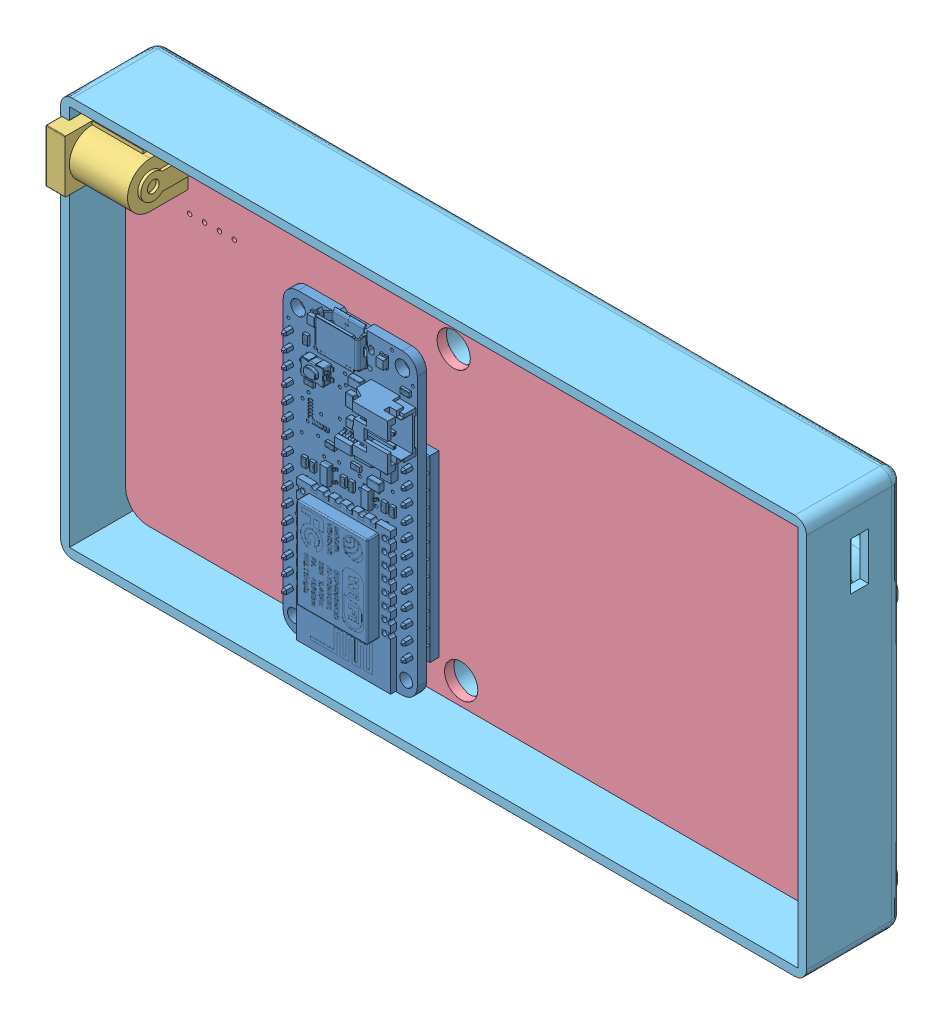
SolidWorks assembly boitierLED, configuration Défaut. Lengths in mm.
Overall size (127 68 83.44).
11 component instances, 5 part files, 1 mates.
Components (placement in the parent):
- me-freeledmodel-1: me-freeledmodel [Défaut] at (-82.6083 85.1585 124.3251) size (125.18 62.87 58.05)
  - Adafruit_ESP8266_Feather_withPinheads-1: Adafruit_ESP8266_Feather_withPinheads [Défaut] at (77.45 -64.5 3.65) x (-1 0 0) z (0 1 0) size (22.89 14.76 51.51)
    - COMPOUND-1: COMPOUND [Défaut] at origin size (22.89 14.76 51.51)
  - R_1206-1: R_1206 [Défaut] at (65.31 -92.71 1.65) size (3.2 1.6 0.55)
    - SOLID-1: SOLID [Défaut] at origin size (3.2 1.6 0.55)
  - R_1206-2: R_1206 [Défaut] at (65.31 -85.09 1.65) size (3.2 1.6 0.55)
    - SOLID-1: SOLID [Défaut] at origin size (3.2 1.6 0.55)
  - barrel-1: barrel [Défaut] at (34.925 -58.547 8.15) size (13.7 9.55 14.6)
    - COMPOUND_2-1: COMPOUND_2 [Défaut] at origin size (13.7 9.55 14.6)
  - COMPOUND_3-1: COMPOUND_3 [Défaut] at origin size (122.77 62.87 1.6)
- coqueinf-1: coqueinf [Défaut] at (-59.5183 -31.7965 134.4251) size (127 68 83.44)
Mates (geometry in assembly coordinates):
- Coïncidente1: coincident aligned: line of me-freeledmodel-1/COMPOUND_3-1 through (2.4817 0.7035 125.9251) axis (0 0 1); line of coqueinf-1 through (2.4817 0.7035 119.4251) axis (0 0 1)
